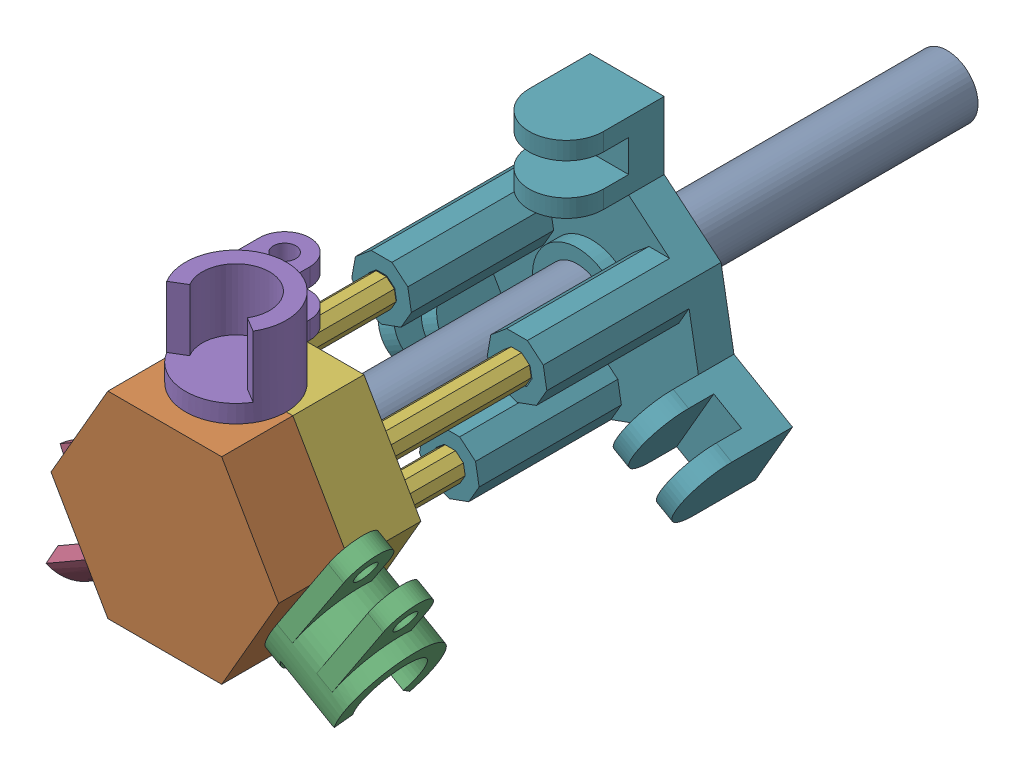
SolidWorks assembly Assem1, configuration Default. Lengths in mm.
Overall size (73.39 73.65 139.53).
7 component instances, 5 part files, 12 mates.
Components (placement in the parent):
- shaft-3: shaft [Default] at origin size (11 11 127)
- nose cone-6: nose cone [Default] at (0 0 76.2) x (1 0 0) z (0 1 0) size (40.64 12.7 35.2) (hidden)
- blade holder - Alyssa-2: blade holder - Alyssa [Default] at (15.24 -8.7988 63.5) x (-0.101531 -0.175856 -0.979166) z (-0.489583 -0.847983 0.203061) size (18 21.18 26.69) (hidden)
- blade holder - Alyssa-3: blade holder - Alyssa [Default] at (-15.24 -8.7988 63.5) x (-0.409846 0.709874 -0.572804) z (-0.286402 0.496063 0.819692) size (18 21.18 26.69)
- blade holder - Alyssa-4: blade holder - Alyssa [Default] at (0 17.5976 63.5) size (18 21.18 26.69)
- slider frame-3: slider frame [Default] at (0 0 50.8) x (-1 0 0) z (0 1 0) size (40.64 38.1 35.2)
- Swashplate-2: Swashplate [Default] at (0 0 -6.35) x (0.34202 0.939693 0) z (0.939693 -0.34202 0) size (58.17 31.75 55.51)
Mates (geometry in assembly coordinates):
- Coincident13: coincident anti-aligned: plane of shaft-3 through (0 0 63.5) normal (0 0 1); plane of nose cone-6 through (0 0 63.5) normal (0 0 -1)
- Coincident24: coincident anti-aligned: plane of nose cone-6 through (10.7105 -2.6442 63.5) normal (0.866025 -0.5 0); plane of blade holder - Alyssa-2 through (9.1778 -5.2988 63.5) normal (-0.866025 0.5 0)
- Concentric4: concentric anti-aligned: circle of nose cone-6; circle of blade holder - Alyssa-2
- Coincident25: coincident anti-aligned: plane of nose cone-6 through (-7.6452 -7.9535 63.5) normal (-0.866025 -0.5 0); plane of blade holder - Alyssa-3 through (-9.1778 -5.2988 63.5) normal (0.866025 0.5 0)
- Concentric6: concentric anti-aligned: circle of nose cone-6; circle of blade holder - Alyssa-3
- Coincident26: coincident anti-aligned: plane of nose cone-6 through (-3.0653 10.5976 63.5) normal (0 1 0); plane of blade holder - Alyssa-4 through (0 10.5976 63.5) normal (0 -1 0)
- Concentric8: concentric anti-aligned: circle of nose cone-6; circle of blade holder - Alyssa-4
- Coincident28: coincident anti-aligned: plane of nose cone-6 through (0 0 63.5) normal (0 0 -1); plane of slider frame-3 through (0 0 63.5) normal (0 0 1)
- Concentric11: concentric aligned: cylinder of shaft-3 through (0 0 63.5) axis (0 0 -1) radius 5.5; cylinder of Swashplate-2 through (0 0 0) axis (0 0 -1) radius 5.5
- LimitDistance1: limit distance = 25.4 mm anti-aligned: plane of Swashplate-2 through (0 0 25.4) normal (0 0 1); plane of slider frame-3 through (0 0 50.8) normal (0 0 -1)
- Parallel8: parallel anti-aligned: plane of slider frame-3 through (13.7131 5.0482 25.4) normal (0.866025 -0.5 0); plane of Swashplate-2
- Parallel9: parallel anti-aligned: plane of slider frame-3 through (0.1778 -16.6333 25.4) normal (0.34202 -0.939693 0); plane of Swashplate-2 through (0 -16.665 25.4) normal (-0.34202 0.939693 0)
